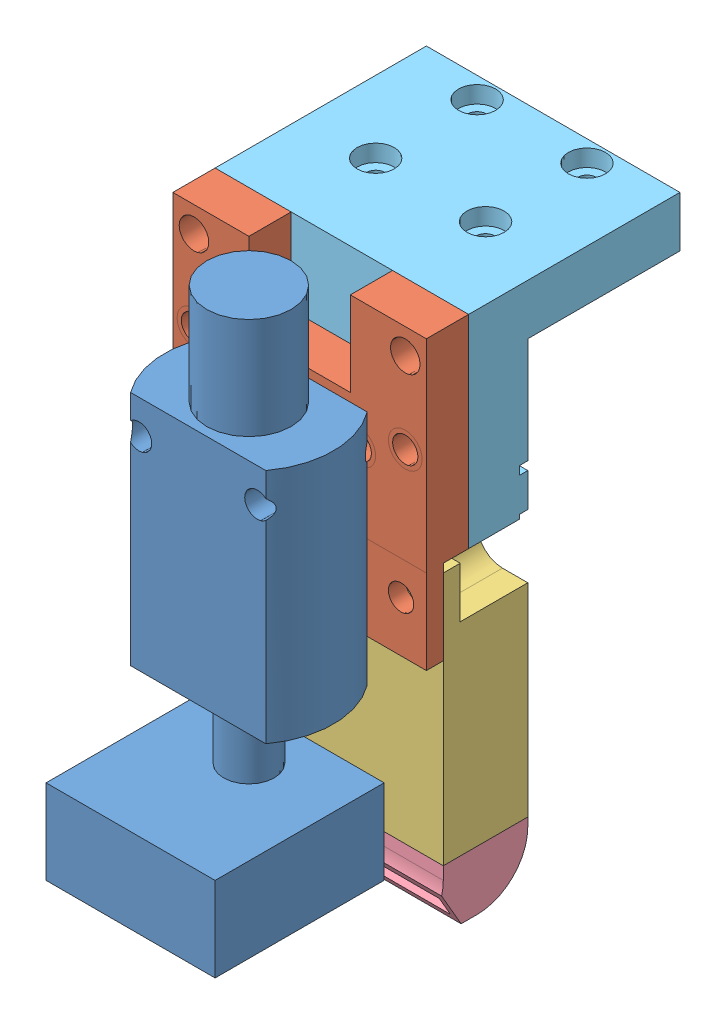
SolidWorks assembly #printer_tool_CR10, configuration Valor predeterminado. Lengths in mm.
Overall size (30 63 50).
5 component instances, 5 part files, 17 mates.
Components (placement in the parent):
- cr10_hotend-1: cr10_hotend [Valor predeterminado] at (6.8325 1.0785 44.4561) x (-1 0 0) z (0 0 -1) size (20 60 20.15)
- cooling fan holder-1: cooling fan holder [Valor predeterminado] at (6.8325 -6.4215 35.4561) size (30 34 5)
- 3010 radial cooling fan-1: 3010 radial cooling fan [Valor predeterminado] at (6.8325 -13.9215 36.4561) x (-1 0 0) z (0 0 -1) size (30 30 10)
- fan duct-1: fan duct [Valor predeterminado] at (9.8325 -28.9215 31.4561) x (0 0 1) z (-1 0 0) size (10.2 12.5 30)
- X_carriage_multitool-1: X_carriage_multitool [Valor predeterminado] at (6.8325 2.0785 26.4561) x (1 0 0) z (0 0 -1) size (30 24 25)
Mates (geometry in assembly coordinates):
- Concêntrico3: concentric anti-aligned: cylinder of printer_tool_CR10-1 through (18.3522 -4.1278 34) axis (0 0 -1) radius 1.6; cylinder of cr10_hotend-1 through (13.8325 11.0785 38.4561) axis (0 0 1) radius 1.5
- Concêntrico4: concentric anti-aligned: cylinder of printer_tool_CR10-1 through (4.3522 -4.1278 34) axis (0 0 -1) radius 1.6; cylinder of cr10_hotend-1 through (-0.1675 11.0785 38.4561) axis (0 0 1) radius 1.5
- Concêntrico7: concentric anti-aligned: cylinder of cooling fan holder-1 through (18.8325 -1.9215 38.4561) axis (0 0 -1) radius 1.5; cylinder of 3010 radial cooling fan-1 through (18.8325 -1.9215 34.4561) axis (0 0 1) radius 1.5
- Coincidente5: coincident aligned: plane of cooling fan holder-1 through (21.8325 -6.4215 38.4561) normal (1 0 0); plane of 3010 radial cooling fan-1 through (21.8325 -13.9215 26.4561) normal (1 0 0)
- Coincidente6: coincident anti-aligned: plane of cooling fan holder-1 through (6.8325 -6.4215 36.4561) normal (0 0 -1); plane of 3010 radial cooling fan-1 through (6.8325 -13.9215 36.4561) normal (0 0 1)
- Concêntrico8: concentric anti-aligned: cylinder of cr10_hotend-1 through (13.8325 11.0785 38.4561) axis (0 0 1) radius 1.5; cylinder of cooling fan holder-1 through (13.8325 11.0785 38.4561) axis (0 0 -1) radius 1.5
- Coincidente8: coincident anti-aligned: plane of cr10_hotend-1 through (6.8325 1.0785 38.4561) normal (0 0 -1); plane of cooling fan holder-1 through (6.8325 -6.4215 38.4561) normal (0 0 1)
- Coincidente9: coincident aligned: plane of printer_tool_CR10-1 through (-3.6478 2.1098 32) normal (-1 0 0); plane of cooling fan holder-1 through (-8.1675 -6.4215 38.4561) normal (-1 0 0)
- Largura1: width anti-aligned: plane of fan duct-1 through (-0.5675 -25.9215 27.4561) normal (0 0 -1); plane of 3010 radial cooling fan-1 through (-0.5675 -25.9215 35.4561) normal (0 0 1); plane of fan duct-1 through (6.8325 -13.9215 34.9561) normal (0 0 -1); plane of 3010 radial cooling fan-1 through (6.8325 -13.9215 27.9561) normal (0 0 1)
- Coincidente10: coincident anti-aligned: plane of 3010 radial cooling fan-1 through (6.8325 -28.9215 26.4561) normal (0 -1 0); plane of fan duct-1 through (-2.1675 -28.9215 26.4561) normal (0 1 0)
- Coincidente11: coincident aligned: plane of 3010 radial cooling fan-1 through (21.8325 -13.9215 26.4561) normal (1 0 0); plane of fan duct-1 through (21.8325 -29.9215 32.4561) normal (1 0 0)
- Coincidente12: coincident aligned: plane of printer_tool_CR10-1 through (-3.6478 2.1098 32) normal (-1 0 0); plane of X_carriage_multitool-1 through (-8.1675 2.0785 26.4561) normal (-1 0 0)
- Coincidente13: coincident anti-aligned: plane of printer_tool_CR10-1 through (11.3522 -10.8902 29) normal (0 0 -1); plane of X_carriage_multitool-1 through (21.8325 26.0785 33.4561) normal (0 0 1)
- Coincidente14: coincident: point of X_carriage_multitool-1; line of printer_tool_CR10-1 through (11.3522 -9.9247 29) axis (0 0.434748 0.900552)
- Coincidente15: coincident anti-aligned: plane of printer_tool_CR10-1 through (11.3522 -10.8902 34) normal (0 0 1); plane of cooling fan holder-1 through (6.8325 -6.4215 35.4561) normal (0 0 -1)
- Concêntrico9: concentric anti-aligned: cylinder of cooling fan holder-1 through (19.3325 23.0785 38.4561) axis (0 0 -1) radius 1.75; cylinder of X_carriage_multitool-1 through (19.3325 23.0785 29.4561) axis (0 0 1) radius 2.075
- Coincidente16: coincident aligned: plane of 3010 radial cooling fan-1 through (6.8325 -13.9215 26.4561) normal (0 0 -1); plane of X_carriage_multitool-1 through (21.8325 2.0785 26.4561) normal (0 0 -1)
